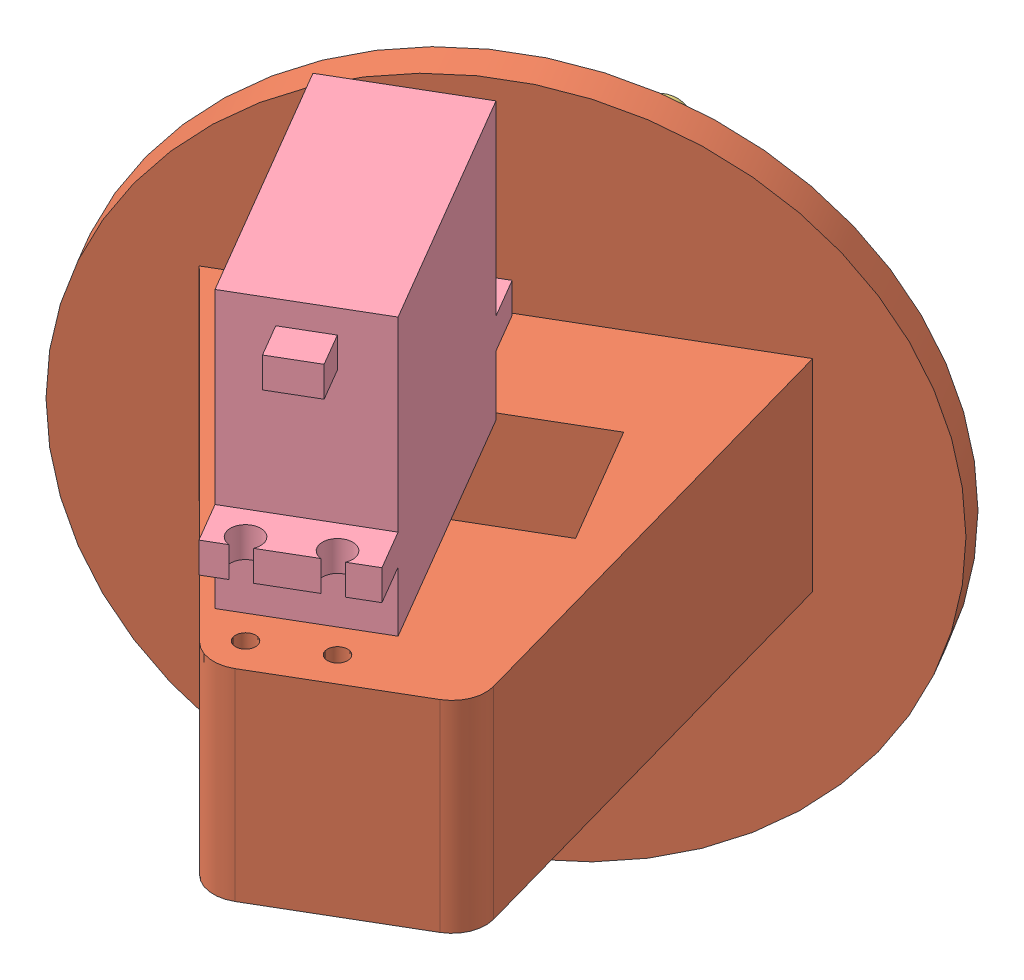
SolidWorks assembly Assem2, configuration Default. Lengths in mm.
Overall size (159.55 111.1 164.75).
5 component instances, 4 part files, 6 mates.
Components (placement in the parent):
- Bearing-1: Bearing [Default] at (7.2074 7.8015 13.9212) size (19 6 19)
- Part2_2-1: Part2_2 [Default] at (-15.3999 17.8015 -36.5755) x (0.86301 0 -0.505188) z (0.505188 0 0.86301) size (100 100 145)
- Bearing-2: Bearing [Default] at (7.2074 17.8015 13.9212) size (19 6 19)
- shaft2-2: shaft2 [Default] at (-46.2163 17.8015 -89.219) x (-0.268135 -0.950509 0.156961) z (0.505188 0 0.86301) size (6 6 84)
- motor-1: motor [Default] at (1.9535 78.9015 4.9459) x (-0.505188 0 -0.86301) z (0 -1 0) size (54.1 19.9 44.8)
Mates (geometry in assembly coordinates):
- Coincident1: coincident anti-aligned: circle of Bearing-1; circle of Part2_2-1
- Coincident2: coincident aligned: circle of Part2_2-1; circle of Bearing-2
- Coincident5: coincident anti-aligned: circle of Part2_2-1; circle of shaft2-2
- Coincident7: coincident anti-aligned: plane of Part2_2-1 through (10.3482 37.8015 29.4637) normal (0 1 0); plane of motor-1 through (1.9535 37.8015 4.9459) normal (0 -1 0)
- Concentric3: concentric anti-aligned: circle of Part2_2-1; circle of motor-1
- Concentric4: concentric anti-aligned: circle of Part2_2-1; circle of motor-1
